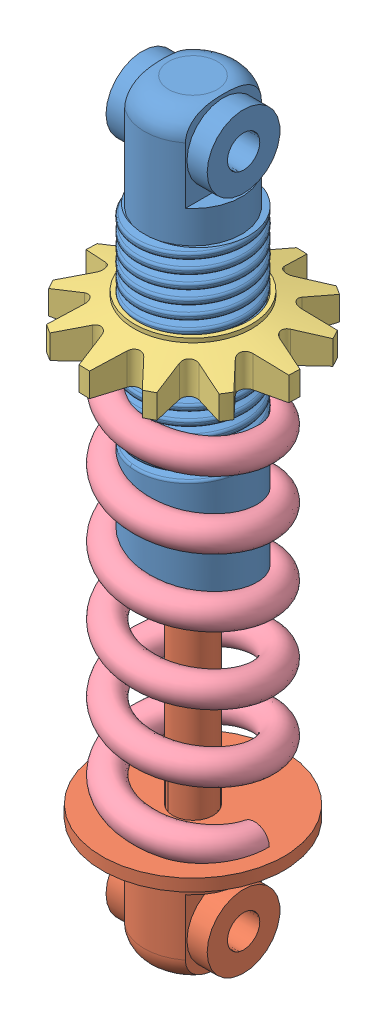
SolidWorks assembly Assem1, configuration Domyślna. Lengths in mm.
Overall size (71.87 186.87 71.87).
4 component instances, 4 part files, 7 mates.
Components (placement in the parent):
- Top_rod-1: Top_rod [Domyślna] at (111.315 -55.1122 108.93) size (28.08 108.93 28.08)
- Base-1: Base [Domyślna] at (111.315 -105.0491 108.93) x (0 0 -1) z (1 0 0) size (45 101 45)
- Nut-1: Nut [Domyślna] at (111.315 -2.1491 108.93) x (-0.682009 0 -0.731344) z (0 1 0) size (50.85 50.85 11.89)
- Spring-1: Spring [Domyślna] at (111.315 -2.1491 108.93) x (0.999924 0 -0.012328) z (0.012328 0 0.999924) size (38.29 107.15 37.25)
Mates (geometry in assembly coordinates):
- Concentric1: concentric aligned: cylinder of Top_rod-1 through (111.315 19.8878 108.93) axis (0 -1 0) radius 5; cylinder of Base-1 through (111.315 -32.0491 108.93) axis (0 -1 0) radius 5
- Concentric2: concentric aligned: cylinder of Top_rod-1 through (111.315 25.8178 108.93) axis (0 -1 0) radius 13.5; cylinder of Nut-1 through (111.315 7.8509 108.93) axis (0 -1 0) radius 14.5
- Screw1: screw = 1 aligned: line of Top_rod-1 through (111.315 25.8178 108.93) axis (0 -1 0); line of Nut-1 through (111.315 7.8509 108.93) axis (0 -1 0)
- Coincident4: coincident aligned: line of Nut-1 through (111.315 7.8509 108.93) axis (0 -1 0); line of Spring-1 through (111.315 -2.1491 108.93) axis (0 -1 0)
- Coincident5: coincident anti-aligned: plane of Nut-1 through (111.315 -2.1491 108.93) normal (0 -1 0); plane of Spring-1 through (111.315 -2.1491 108.93) normal (0 1 0)
- Coincident6: coincident anti-aligned: plane of Base-1 through (111.315 -102.0491 108.93) normal (0 1 0); plane of Spring-1 through (111.315 -102.0491 108.93) normal (0 -1 0)
- Parallel1: parallel anti-aligned: plane of Base-1 through (98.815 -123.0491 108.93) normal (-1 0 0)
